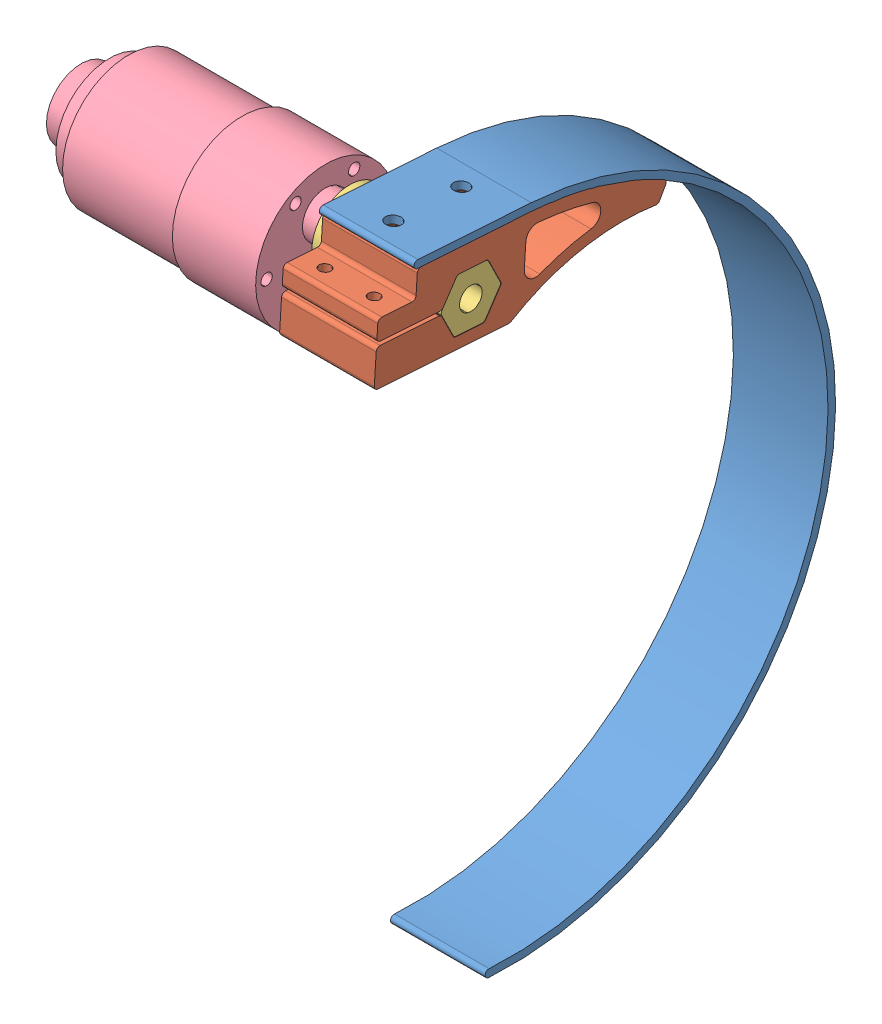
SolidWorks assembly leg assembly, configuration Default. Lengths in mm.
Overall size (103 179.3 128.02).
4 component instances, 4 part files, 8 mates.
Components (placement in the parent):
- curve prop-1: curve prop [Default] at (-218.0947 19.5416 134.3025) x (1 0 0) z (0 0.065545 0.99785) size (25 172 117)
- Part6-1: Part6 [Default] at (-218.0947 17.8883 124.3895) x (1 0 0) z (0 0.065545 0.99785) size (25 23 76.39)
- shaft extension-1: shaft extension [Default] at (-218.0947 90.791 134.6747) x (0 0.99785 -0.065545) z (-1 0 0) size (20 20 32)
- gearnotor_w_encoder-1: gearnotor_w_encoder [Default] at (-253.5947 83.7913 134.6137) x (0 -0.008714 0.999962) z (1 0 0) size (36.8 36.8 86.5)
Mates (geometry in assembly coordinates):
- Coincident4: coincident anti-aligned: plane of curve prop-1 through (-193.0947 102.7055 118.8182) normal (0 -0.99785 0.065545); plane of Part6-1 through (-193.0947 102.7055 118.8182) normal (0 0.99785 -0.065545)
- Concentric1: concentric aligned: cylinder of curve prop-1 through (-205.5947 105.0945 124.6742) axis (0 0.99785 -0.065545) radius 2; cylinder of Part6-1 through (-205.5947 103.0988 124.8053) axis (0 0.99785 -0.065545) radius 1.65
- Concentric2: concentric aligned: cylinder of curve prop-1 through (-205.5947 106.2743 142.6355) axis (0 0.99785 -0.065545) radius 2; cylinder of Part6-1 through (-205.5947 104.2786 142.7666) axis (0 0.99785 -0.065545) radius 1.65
- Coincident5: coincident anti-aligned: plane of shaft extension-1 through (-225.0947 89.6988 118.0467) normal (-1 0 0); plane of gearnotor_w_encoder-1 through (-225.0947 90.3542 128.0252) normal (1 0 0)
- Concentric3: concentric aligned: cylinder of shaft extension-1 through (-218.0947 90.3542 128.0252) axis (-1 0 0) radius 3; cylinder of gearnotor_w_encoder-1 through (-209.5947 90.3542 128.0252) axis (-1 0 0) radius 3
- Coincident6: coincident aligned: plane of Part6-1 through (-193.0947 17.8883 124.3895) normal (1 0 0); plane of shaft extension-1 through (-193.0947 90.5944 131.6812) normal (1 0 0)
- Coincident7: coincident anti-aligned: plane of Part6-1 through (-193.0947 97.4367 130.1465) normal (0 -0.99785 0.065545); plane of shaft extension-1 through (-218.0947 97.7043 134.2206) normal (0 0.99785 -0.065545)
- Coincident8: coincident anti-aligned: plane of Part6-1 through (-193.0947 97.9665 138.212) normal (0 -0.555688 -0.831391); plane of shaft extension-1 through (-218.0947 94.6409 140.4347) normal (0 0.555688 0.831391)
